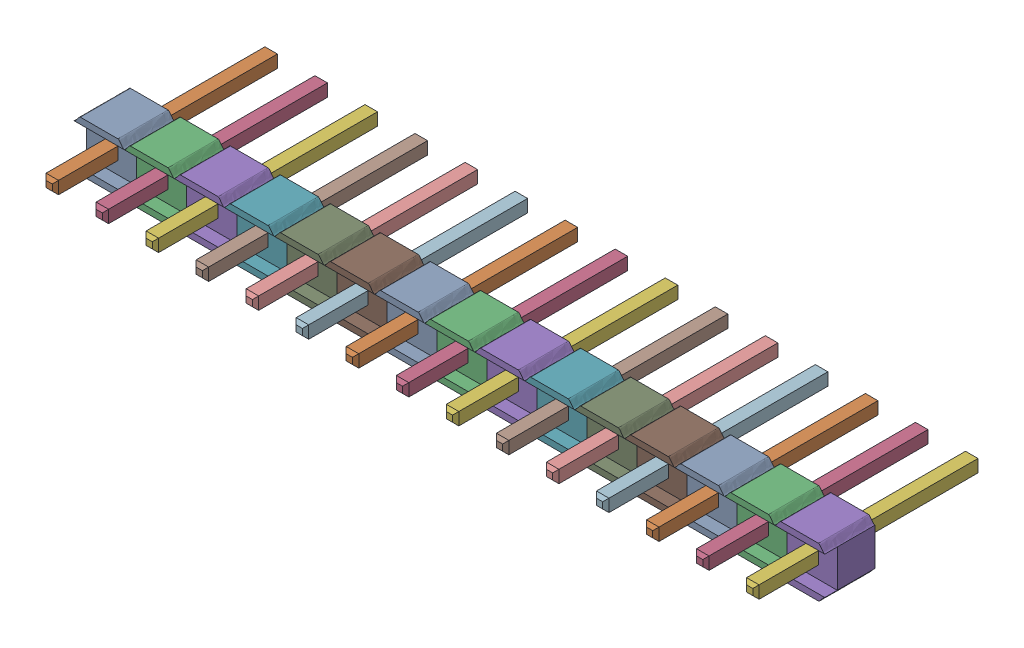
SolidWorks assembly Pin Header 1x15 TH Pitch 2.54mm v3 v1 (1) (1), configuration Default. Lengths in mm.
Overall size (38.1 2.59 11.43).
45 component instances, 2 part files, 0 mates.
Components (placement in the parent):
- asm_pin (1) (1)-1: asm_pin (1) (1) [Default] at (-4.318 1.27 0.0014) x (1 0 0) z (0 0 -1) size (2.54 2.59 11.43)
  - spacer (1) (1)-1: spacer (1) (1) [Default] at origin size (2.54 2.59 2.54)
  - pin (1) (1)-1: pin (1) (1) [Default] at origin size (0.64 0.64 11.43)
- asm_pin (1) (1)_1-1: asm_pin (1) (1)_1 [Default] at (-1.778 1.27 0.0014) x (1 0 0) z (0 0 -1) size (2.54 2.59 11.43)
  - spacer (1) (1)-1: spacer (1) (1) [Default] at origin size (2.54 2.59 2.54)
  - pin (1) (1)-1: pin (1) (1) [Default] at origin size (0.64 0.64 11.43)
- asm_pin (1) (1)_2-1: asm_pin (1) (1)_2 [Default] at (0.762 1.27 0.0014) x (1 0 0) z (0 0 -1) size (2.54 2.59 11.43)
  - spacer (1) (1)-1: spacer (1) (1) [Default] at origin size (2.54 2.59 2.54)
  - pin (1) (1)-1: pin (1) (1) [Default] at origin size (0.64 0.64 11.43)
- asm_pin (1) (1)_3-1: asm_pin (1) (1)_3 [Default] at (3.302 1.27 0.0014) x (1 0 0) z (0 0 -1) size (2.54 2.59 11.43)
  - spacer (1) (1)-1: spacer (1) (1) [Default] at origin size (2.54 2.59 2.54)
  - pin (1) (1)-1: pin (1) (1) [Default] at origin size (0.64 0.64 11.43)
- asm_pin (1) (1)_4-1: asm_pin (1) (1)_4 [Default] at (5.842 1.27 0.0014) x (1 0 0) z (0 0 -1) size (2.54 2.59 11.43)
  - spacer (1) (1)-1: spacer (1) (1) [Default] at origin size (2.54 2.59 2.54)
  - pin (1) (1)-1: pin (1) (1) [Default] at origin size (0.64 0.64 11.43)
- asm_pin (1) (1)_5-1: asm_pin (1) (1)_5 [Default] at (8.382 1.27 0.0014) x (1 0 0) z (0 0 -1) size (2.54 2.59 11.43)
  - spacer (1) (1)-1: spacer (1) (1) [Default] at origin size (2.54 2.59 2.54)
  - pin (1) (1)-1: pin (1) (1) [Default] at origin size (0.64 0.64 11.43)
- asm_pin (1) (1)_6-1: asm_pin (1) (1)_6 [Default] at (10.922 1.27 0.0014) x (1 0 0) z (0 0 -1) size (2.54 2.59 11.43)
  - spacer (1) (1)-1: spacer (1) (1) [Default] at origin size (2.54 2.59 2.54)
  - pin (1) (1)-1: pin (1) (1) [Default] at origin size (0.64 0.64 11.43)
- asm_pin (1) (1)_7-1: asm_pin (1) (1)_7 [Default] at (13.462 1.27 0.0014) x (1 0 0) z (0 0 -1) size (2.54 2.59 11.43)
  - spacer (1) (1)-1: spacer (1) (1) [Default] at origin size (2.54 2.59 2.54)
  - pin (1) (1)-1: pin (1) (1) [Default] at origin size (0.64 0.64 11.43)
- asm_pin (1) (1)_8-1: asm_pin (1) (1)_8 [Default] at (16.002 1.27 0.0014) x (1 0 0) z (0 0 -1) size (2.54 2.59 11.43)
  - spacer (1) (1)-1: spacer (1) (1) [Default] at origin size (2.54 2.59 2.54)
  - pin (1) (1)-1: pin (1) (1) [Default] at origin size (0.64 0.64 11.43)
- asm_pin (1) (1)_9-1: asm_pin (1) (1)_9 [Default] at (18.542 1.27 0.0014) x (1 0 0) z (0 0 -1) size (2.54 2.59 11.43)
  - spacer (1) (1)-1: spacer (1) (1) [Default] at origin size (2.54 2.59 2.54)
  - pin (1) (1)-1: pin (1) (1) [Default] at origin size (0.64 0.64 11.43)
- asm_pin (1) (1)_10-1: asm_pin (1) (1)_10 [Default] at (21.082 1.27 0.0014) x (1 0 0) z (0 0 -1) size (2.54 2.59 11.43)
  - spacer (1) (1)-1: spacer (1) (1) [Default] at origin size (2.54 2.59 2.54)
  - pin (1) (1)-1: pin (1) (1) [Default] at origin size (0.64 0.64 11.43)
- asm_pin (1) (1)_11-1: asm_pin (1) (1)_11 [Default] at (23.622 1.27 0.0014) x (1 0 0) z (0 0 -1) size (2.54 2.59 11.43)
  - spacer (1) (1)-1: spacer (1) (1) [Default] at origin size (2.54 2.59 2.54)
  - pin (1) (1)-1: pin (1) (1) [Default] at origin size (0.64 0.64 11.43)
- asm_pin (1) (1)_12-1: asm_pin (1) (1)_12 [Default] at (26.1619 1.27 0.0014) x (1 0 0) z (0 0 -1) size (2.54 2.59 11.43)
  - spacer (1) (1)-1: spacer (1) (1) [Default] at origin size (2.54 2.59 2.54)
  - pin (1) (1)-1: pin (1) (1) [Default] at origin size (0.64 0.64 11.43)
- asm_pin (1) (1)_13-1: asm_pin (1) (1)_13 [Default] at (28.702 1.27 0.0014) x (1 0 0) z (0 0 -1) size (2.54 2.59 11.43)
  - spacer (1) (1)-1: spacer (1) (1) [Default] at origin size (2.54 2.59 2.54)
  - pin (1) (1)-1: pin (1) (1) [Default] at origin size (0.64 0.64 11.43)
- asm_pin (1) (1)_14-1: asm_pin (1) (1)_14 [Default] at (31.242 1.27 0.0014) x (1 0 0) z (0 0 -1) size (2.54 2.59 11.43)
  - spacer (1) (1)-1: spacer (1) (1) [Default] at origin size (2.54 2.59 2.54)
  - pin (1) (1)-1: pin (1) (1) [Default] at origin size (0.64 0.64 11.43)
